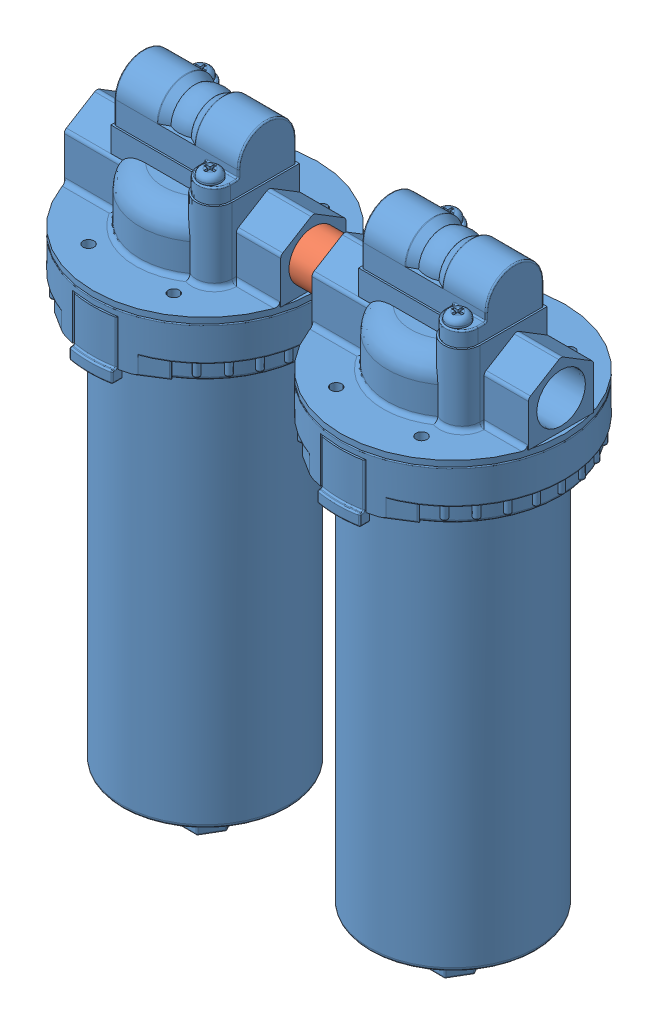
SolidWorks assembly ReadingTech_4P-060-M04-DCi, configuration Default. Lengths in mm.
Overall size (206.63 278.26 99.95).
3 component instances, 2 part files, 3 mates.
Components (placement in the parent):
- ReadingTech_3P-060-M04-Fi-1: ReadingTech_3P-060-M04-Fi [Default] at (-32.8687 -95.9408 1.7822) size (98.17 278.26 99.95)
- ReadingTech_3P-060-M04-Fi-2: ReadingTech_3P-060-M04-Fi [Default] at (75.5893 -95.9408 1.7822) size (98.17 278.26 99.95)
- ReadingTech- 60cfm_connector_.5in-1: ReadingTech- 60cfm_connector_.5in [Default] at (28.2183 119.9592 1.7822) x (0 0.479535 0.877523) z (0 -0.877523 0.479535) size (21.34 13.72 21.34)
Mates (geometry in assembly coordinates):
- Coincident1: coincident anti-aligned: circle of ReadingTech_3P-060-M04-Fi-1; circle of ReadingTech- 60cfm_connector_.5in-1
- Coincident2: coincident aligned: circle of ReadingTech_3P-060-M04-Fi-2; circle of ReadingTech- 60cfm_connector_.5in-1
- Coincident3: coincident aligned: plane of ReadingTech_3P-060-M04-Fi-1 through (14.5023 107.2592 16.0697) normal (0 0 1); plane of ReadingTech_3P-060-M04-Fi-2 through (122.9603 107.2592 16.0697) normal (0 0 1)
